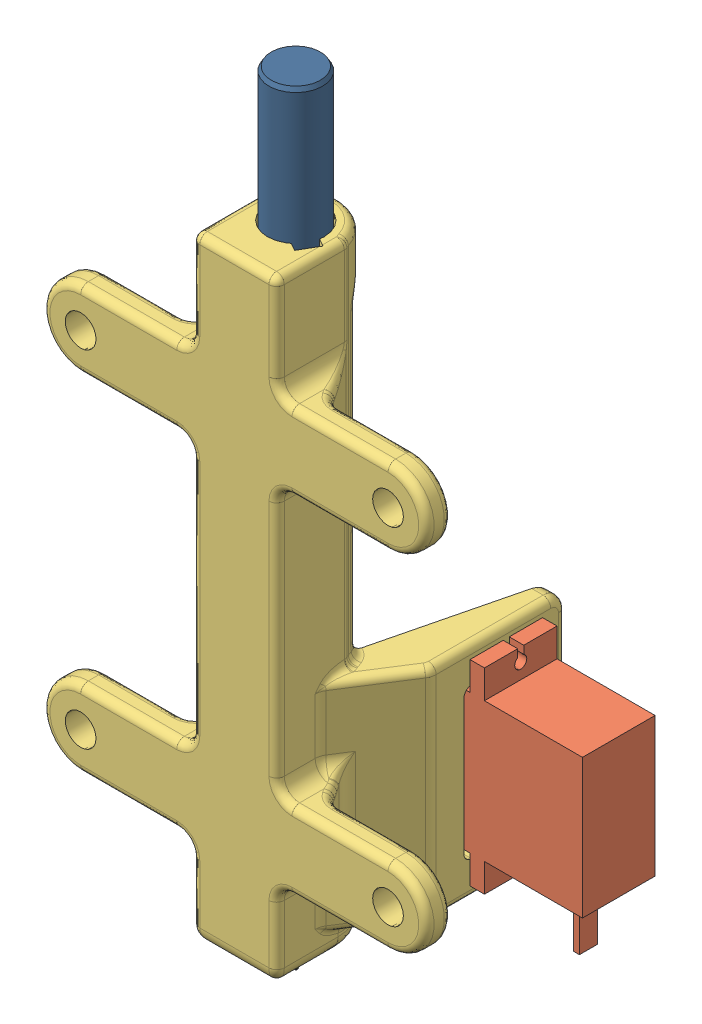
SolidWorks assembly PenHolder, configuration Default. Lengths in mm.
Overall size (64.55 129.45 48.11).
12 component instances, 11 part files, 16 mates.
Components (placement in the parent):
- Servo Lever-1: Servo Lever [Default] at (-0.5 -33.948 -30.734) x (0 -0.984808 -0.173648) z (0 -0.173648 0.984808) size (7.3 5 34)
- SG90 Servo-1: SG90 Servo [Default] at (9.8 -28.448 -30.734) x (0 1 0) z (0 0 1) size (37.7 30.3 12)
- PenHolder-1: PenHolder [Default] at origin size (63.5 101.91 40.64)
- Assembly Ink Cartridge Pilot G2-1: Assembly Ink Cartridge Pilot G2 [Default] at (-23.3837 82.6746 -54.1169) x (1 0 0) z (0 -1 0) size (8.33 8.33 120.93)
  - Ink Container Tube-2: Ink Container Tube [Default] at (23.3837 43.9569 29.8776) x (-1 0 0) z (0 1 0) size (6.2 88 6)
  - Ink Container Back Plug-1: Ink Container Back Plug [Default] at (23.3837 43.9569 29.8776) x (1 0 0) z (0 1 0) size (6 4.9 6)
  - Pen Tip Holder-1: Pen Tip Holder [Default] at (23.3837 43.9569 117.8776) x (0.558829 -0.829283 0) z (0.829283 0.558829 0) size (6 18.11 6)
  - Pen Tip-1: Pen Tip [Default] at (23.3837 43.9569 135.6644) x (0.943336 0.33184 0) z (-0.33184 0.943336 0) size (2.59 15.69 2.63)
  - Roller Ball-2: Roller Ball [Default] at (23.3837 43.9569 138.8644) x (0.307657 -0.299861 -0.903012) z (0.951494 0.099481 0.29114) size (0.5 0.5 0.5)
  - Spring-3: Spring [Write] at (23.3837 43.9569 20.2276) x (1 0 0) z (0 -1 0) size (7.26 11.16 7.26)
- Spring Cap-1: Spring Cap [Default] at (0 19.5395 -10.16) x (0.422618 0 0.906308) z (-0.906308 0 0.422618) size (8.89 53.34 10.92)
- Pen Lifter-1: Pen Lifter [Default] at (0 -47.625 -10.16) x (-1 0 0) z (0 0 -1) size (8.89 15.4 11.43)
Mates (geometry in assembly coordinates):
- Concentric1: concentric anti-aligned: cylinder of Servo Lever-1 through (4.5 -33.948 -30.734) axis (-1 0 0) radius 0.75; cylinder of SG90 Servo-1 through (5.5 -33.948 -30.734) axis (1 0 0) radius 6
- Coincident2: coordinate: point of PenHolder-1
- Concentric4: concentric anti-aligned: cylinder of PenHolder-1 through (0 -47.625 -10.16) axis (0 -1 0) radius 1.397; cylinder of Assembly Ink Cartridge Pilot G2-1/Ink Container Tube-2 through (0 -35.203 -10.16) axis (0 1 0) radius 3
- Coincident7: coincident anti-aligned: plane of Servo Lever-1 through (2.5 -33.948 -30.734) normal (1 0 0); plane of SG90 Servo-1 through (2.5 -28.448 -30.734) normal (-1 0 0)
- Parallel2: parallel aligned: plane of Assembly Ink Cartridge Pilot G2-1 through (-23.3837 82.6746 -54.1169) normal (0 0 1)
- Concentric5: concentric anti-aligned: cylinder of PenHolder-1 through (0 50.8 -10.16) axis (0 -1 0) radius 6.985; cylinder of Spring Cap-1 through (0 70.3395 -10.16) axis (0 1 0) radius 4.445
- Angle1: planar angle = 2.007129 rad anti-aligned: plane of Spring Cap-1 through (0 19.5395 -10.16) normal (-0.906308 0 0.422618)
- Concentric7: concentric anti-aligned: cylinder of PenHolder-1 through (0 50.8 -10.16) axis (0 -1 0) radius 4.699; cylinder of Pen Lifter-1 through (0 -36.703 -10.16) axis (0 1 0) radius 4.445
- Parallel5: parallel anti-aligned: plane of Pen Lifter-1 through (0 -47.625 -10.16) normal (0 0 -1)
- Symmetric2: symmetric aligned: plane of Servo Lever-1 through (-0.5 -31.3867 -45.2599) normal (-1 0 0); plane of Servo Lever-1 through (0.5 -31.3867 -45.2599) normal (1 0 0); plane of Pen Lifter-1 through (0 -47.625 -10.16) normal (-1 0 0)
- LimitAngle1: limit planar angle = 0.174533 rad aligned: plane of Servo Lever-1 through (-0.5 -33.948 -30.734) normal (0 -0.173648 0.984808); plane of SG90 Servo-1 through (9.8 -28.448 -30.734) normal (0 0 1)
- LimitDistance1: limit distance = 0 mm anti-aligned: plane of PenHolder-1 through (0 -47.625 -10.16) normal (0 1 0); plane of Pen Lifter-1 through (-4.445 -47.625 -10.16) normal (0 -1 0)
- Coincident14: coincident anti-aligned: plane of Assembly Ink Cartridge Pilot G2-1/Pen Tip Holder-1 through (0 -36.703 -10.16) normal (0 -1 0); plane of Pen Lifter-1 through (-2.3546 -36.703 -10.16) normal (0 1 0)
- Parallel6: parallel anti-aligned: plane of SG90 Servo-1 through (14.2 -28.448 -30.734) normal (-1 0 0); plane of PenHolder-1 through (14.2011 0 0) normal (1 0 0)
- Concentric8: concentric anti-aligned: cylinder of SG90 Servo-1 through (16.6 -14.4196 -30.734) axis (-1 0 0) radius 1; cylinder of PenHolder-1 through (11.6611 -14.4196 -30.734) axis (1 0 0) radius 0.635
- Parallel7: parallel aligned: plane of SG90 Servo-1 through (32.8 -39.948 -36.734) normal (0 0 -1); plane of PenHolder-1 through (11.6611 -12.248 -40.64) normal (0 0 -1)
